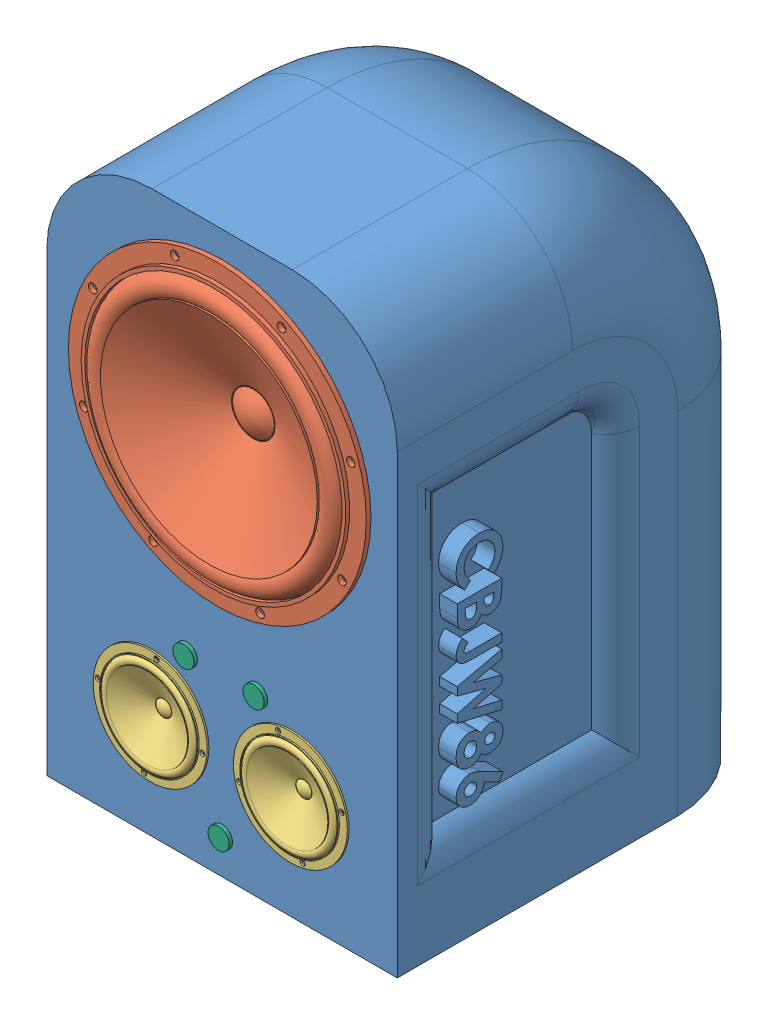
SolidWorks assembly SpeakerAssembl, configuration Default. Lengths in mm.
Overall size (100 160.32 113.94).
12 component instances, 7 part files, 27 mates.
Components (placement in the parent):
- speakerCAD-1: speakerCAD [Default] at (56.9986 106.0943 64.7796) size (100 160 110)
- Speaker_Driver_80mm-1: Speaker_Driver_80mm [Default] at (56.9986 136.0943 159.1683) size (85 85 31.97)
- Speaker_Driver_30mm-1: Speaker_Driver_30mm [Default] at (76.9986 56.0943 168.9254) x (0.756716 0.653743 0) z (0 0 1) size (32.5 32.5 11.99)
- Speaker_Driver_30mm-2: Speaker_Driver_30mm [Default] at (36.9986 56.0943 168.9254) x (0.93732 0.34847 0) z (0 0 1) size (32.5 32.5 11.99)
- Speaker_Button_Mount-1: Speaker_Button_Mount [Default] at (33.2599 61.6367 154.7796) x (-1 0 0) z (0 1 0) size (11.25 21 9.5)
- Speaker_Button_Mount-2: Speaker_Button_Mount [Default] at (13.2599 61.6367 154.7796) x (-1 0 0) z (0 1 0) size (11.25 21 9.5)
- Speaker_Button_Mount-3: Speaker_Button_Mount [Default] at (42.541 69.833 154.7796) x (0 1 0) z (1 0 0) size (11.25 21 9.5)
- Speaker_PCB-2: Speaker_PCB [Default] at (81.5251 46.8443 135.3592) x (1 0 0) z (0 1 0) size (55 50 17.5)
- ButtonCaps-1: ButtonCaps [Default] at (56.9986 36.0943 175.7796) x (1 0 0) z (0 0 -1) size (6 6 20)
- ButtonCaps-2: ButtonCaps [Default] at (46.9986 76.0943 175.7796) x (-0.964828 -0.262882 0) z (0 0 -1) size (6 6 20)
- ButtonCaps-3: ButtonCaps [Default] at (66.9986 76.0943 175.7796) x (-0.841297 -0.540574 0) z (0 0 -1) size (6 6 20)
- Base PLug-1: Base PLug [Default] at (56.9986 25.7693 125.734) x (-0.341232 0 -0.939979) z (0.939979 0 -0.341232) size (70 4.7 70)
Mates (geometry in assembly coordinates):
- Concentric1: concentric aligned: cylinder of speakerCAD-1 through (56.9986 136.0943 154.7796) axis (0 0 1) radius 40; cylinder of Speaker_Driver_80mm-1 through (56.9986 136.0943 149.5683) axis (0 0 1) radius 14.1177
- Coincident2: coincident anti-aligned: plane of speakerCAD-1 through (56.9986 106.0943 174.7796) normal (0 0 1); plane of Speaker_Driver_80mm-1 through (18.799 136.0943 174.7796) normal (0 0 -1)
- Concentric2: concentric aligned: cylinder of speakerCAD-1 through (36.9986 56.0943 154.7796) axis (0 0 1) radius 15; cylinder of Speaker_Driver_30mm-2 through (36.9986 56.0943 165.3254) axis (0 0 1) radius 5.2941
- Coincident3: coincident anti-aligned: plane of speakerCAD-1 through (56.9986 106.0943 174.7796) normal (0 0 1); plane of Speaker_Driver_30mm-2 through (23.5717 51.1025 174.7796) normal (0 0 -1)
- Concentric3: concentric aligned: cylinder of speakerCAD-1 through (76.9986 56.0943 154.7796) axis (0 0 1) radius 15; cylinder of Speaker_Driver_30mm-1 through (76.9986 56.0943 165.3254) axis (0 0 1) radius 5.2941
- Coincident4: coincident anti-aligned: plane of speakerCAD-1 through (56.9986 106.0943 174.7796) normal (0 0 1); plane of Speaker_Driver_30mm-1 through (66.1588 46.7295 174.7796) normal (0 0 -1)
- Coincident6: coincident aligned: plane of speakerCAD-1 through (6.9986 26.0943 174.7796) normal (-1 0 0); plane of Speaker_PCB-2 through (6.9986 41.0943 106.0196) normal (-1 0 0)
- Parallel1: parallel aligned: plane of speakerCAD-1 through (6.9986 26.0943 174.7796) normal (0 -1 0); plane of Speaker_PCB-2 through (32.418 45.8443 144.3946) normal (0 -1 0)
- Coincident9: coincident aligned: plane of speakerCAD-1 through (6.9986 26.0943 174.7796) normal (-1 0 0); plane of Speaker_PCB-2 through (6.9986 41.0943 144.7696) normal (-1 0 0)
- Concentric6: concentric anti-aligned: cylinder of Speaker_Button_Mount-3 through (56.9986 36.0943 165.7796) axis (0 0 -1) radius 2; cylinder of ButtonCaps-1 through (56.9986 36.0943 155.7796) axis (0 0 1) radius 2
- Coincident14: coincident anti-aligned: plane of Speaker_Button_Mount-3 through (56.9986 36.0943 165.7796) normal (0 0 1); plane of ButtonCaps-1 through (56.9986 36.0943 165.7796) normal (0 0 -1)
- Coincident15: coincident anti-aligned: plane of speakerCAD-1 through (76.9986 56.0943 154.7796) normal (0 0 -1); plane of Speaker_Button_Mount-3 through (61.7486 41.7193 154.7796) normal (0 0 1)
- Concentric8: concentric aligned: cylinder of speakerCAD-1 through (56.9986 36.0943 154.7796) axis (0 0 1) radius 3; cylinder of ButtonCaps-1 through (56.9986 36.0943 155.7796) axis (0 0 1) radius 3
- Parallel2: parallel aligned: plane of speakerCAD-1 through (6.9986 26.0943 174.7796) normal (0 -1 0); plane of Speaker_Button_Mount-3 through (52.2486 30.4693 144.7796) normal (0 -1 0)
- Concentric9: concentric anti-aligned: cylinder of Speaker_Button_Mount-1 through (66.9986 76.0943 165.7796) axis (0 0 -1) radius 2; cylinder of ButtonCaps-3 through (66.9986 76.0943 155.7796) axis (0 0 1) radius 2
- Coincident17: coincident anti-aligned: plane of Speaker_Button_Mount-1 through (66.9986 76.0943 165.7796) normal (0 0 1); plane of ButtonCaps-3 through (66.9986 76.0943 165.7796) normal (0 0 -1)
- Concentric10: concentric anti-aligned: cylinder of Speaker_Button_Mount-2 through (46.9986 76.0943 165.7796) axis (0 0 -1) radius 2; cylinder of ButtonCaps-2 through (46.9986 76.0943 155.7796) axis (0 0 1) radius 2
- Coincident18: coincident anti-aligned: plane of Speaker_Button_Mount-2 through (46.9986 76.0943 165.7796) normal (0 0 1); plane of ButtonCaps-2 through (46.9986 76.0943 165.7796) normal (0 0 -1)
- Concentric11: concentric aligned: cylinder of speakerCAD-1 through (66.9986 76.0943 154.7796) axis (0 0 1) radius 3; cylinder of ButtonCaps-3 through (66.9986 76.0943 155.7796) axis (0 0 1) radius 3
- Coincident19: coincident anti-aligned: plane of speakerCAD-1 through (76.9986 56.0943 154.7796) normal (0 0 -1); plane of Speaker_Button_Mount-1 through (61.3736 80.8443 154.7796) normal (0 0 1)
- Parallel3: parallel aligned: plane of speakerCAD-1 through (6.9986 26.0943 174.7796) normal (0 -1 0); plane of Speaker_Button_Mount-1 through (70.1236 71.3443 144.7796) normal (0 -1 0)
- Concentric12: concentric aligned: cylinder of speakerCAD-1 through (46.9986 76.0943 154.7796) axis (0 0 1) radius 3; cylinder of ButtonCaps-2 through (46.9986 76.0943 155.7796) axis (0 0 1) radius 3
- Coincident21: coincident anti-aligned: plane of speakerCAD-1 through (76.9986 56.0943 154.7796) normal (0 0 -1); plane of Speaker_Button_Mount-2 through (41.3736 80.8443 154.7796) normal (0 0 1)
- Parallel4: parallel aligned: plane of speakerCAD-1 through (6.9986 26.0943 174.7796) normal (0 -1 0); plane of Speaker_Button_Mount-2 through (50.1236 71.3443 144.7796) normal (0 -1 0)
- Concentric13: concentric anti-aligned: cylinder of speakerCAD-1 through (16.9986 41.0943 106.0196) axis (-1 0 0) radius 2.75; cylinder of Speaker_PCB-2 through (6.9986 41.0943 106.0196) axis (1 0 0) radius 2.75
- Concentric14: concentric aligned: cylinder of speakerCAD-1 through (56.9986 36.0943 125.734) axis (0 -1 0) radius 35; cylinder of Base PLug-1 through (56.9986 30.4693 125.734) axis (0 -1 0) radius 35
- Coincident23: coincident anti-aligned: plane of Speaker_Button_Mount-3 through (52.2486 30.4693 144.7796) normal (0 -1 0); plane of Base PLug-1 through (56.9986 30.4693 125.734) normal (0 1 0)
